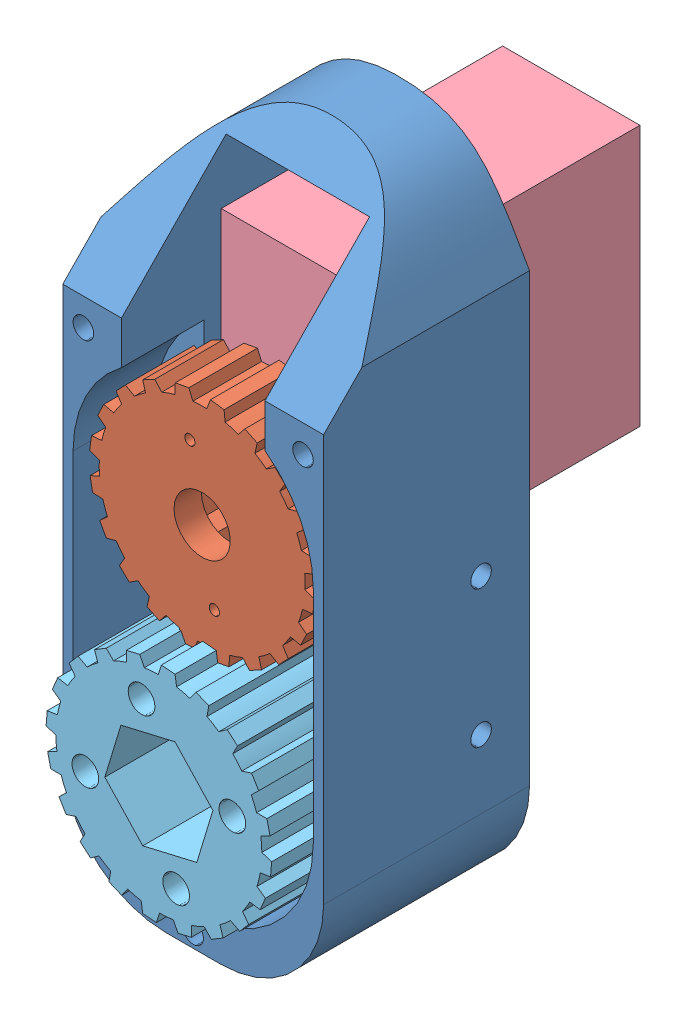
SolidWorks assembly neck gearbox assm, configuration Default. Lengths in mm.
Overall size (39.45 96.66 60).
5 component instances, 5 part files, 11 mates.
Components (placement in the parent):
- neckrot-1: neckrot [Default] at (-18.8555 82.5868 -30) x (0 1 0) z (0 0 1) size (96.66 38 30)
- neckrotlarge-1: neckrotlarge [Default] at (-18.5503 85.67 -1) x (0.178477 -0.983944 0) z (0 0 -1) size (32.81 32.81 10)
- 608ZZ-2: 608ZZ [Default] at (-18.8555 54.5868 -19) x (0.954114 0.299442 0) z (0 0 1) size (22 22 7)
- servo standard-1: servo standard [Default] at (-18.5503 113.97 -34.0202) x (0 0 -1) z (0 -1 0) size (49 20 52)
- neckrotlarge mount-1: neckrotlarge mount [Default] at (-18.8555 54.5868 -12) x (0.97341 0.229069 0) z (0 0 1) size (32.81 32.81 17)
Mates (geometry in assembly coordinates):
- Concentric3: concentric anti-aligned: circle of neckrot-1; circle of servo standard-1
- Coincident1: coincident anti-aligned: plane of neckrot-1 through (-29.3012 122.4868 -28) normal (0 0 1); plane of servo standard-1 through (-80.8348 120.97 -28) normal (0 0 -1)
- Parallel1: parallel aligned: line of neckrot-1; line of servo standard-1
- Concentric4: concentric aligned: circle of neckrotlarge-1; circle of servo standard-1
- Distance1: distance = 3 mm anti-aligned: plane of neckrotlarge-1 through (-18.5503 85.67 -11) normal (0 0 -1); plane of servo standard-1 through (-8.7747 75.97 -14) normal (0 0 1)
- Concentric5: concentric aligned: circle of 608ZZ-2; circle of neckrot-1
- Coincident4: coincident anti-aligned: circle of neckrot-1; plane of 608ZZ-2 through (-18.8555 54.5868 -19) normal (0 0 -1)
- Concentric7: concentric anti-aligned: circle of 608ZZ-2; circle of neckrotlarge mount-1
- Coincident6: coincident anti-aligned: plane of 608ZZ-2 through (-18.8555 54.5868 -12) normal (0 0 1); plane of neckrotlarge mount-1 through (-18.8555 54.5868 -12) normal (0 0 -1)
- Coincident7: coincident aligned: unknown of neckrot-1
- Parallel2: parallel anti-aligned: unknown of neckrot-1
